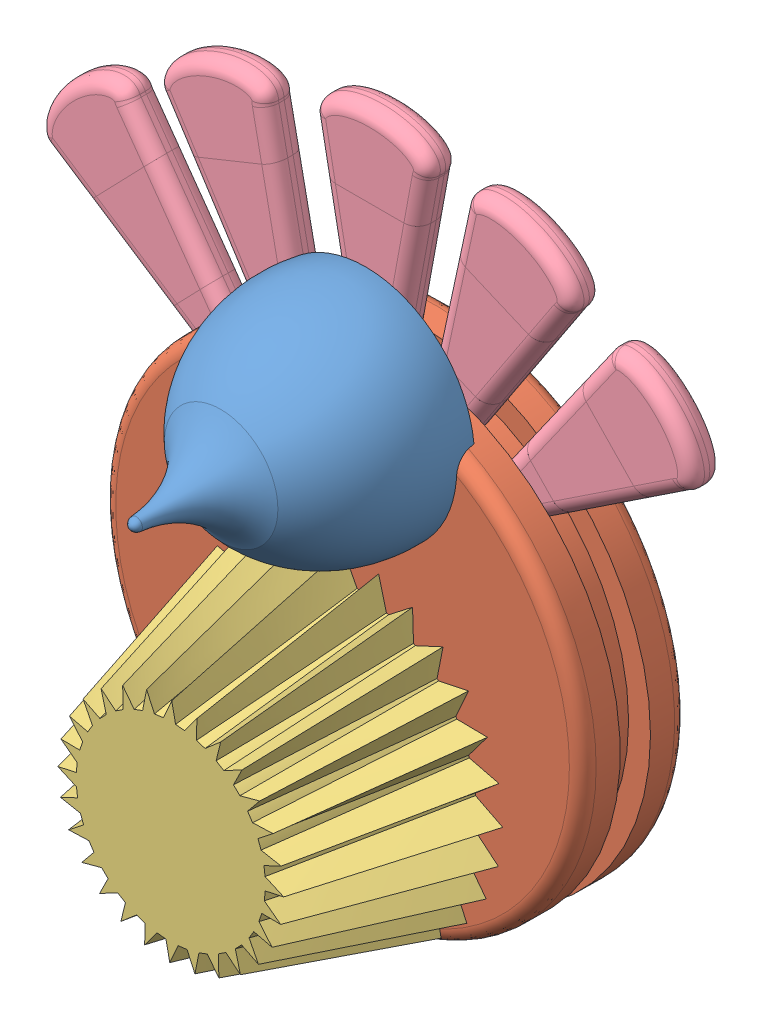
SolidWorks assembly Turkey, configuration Default. Lengths in mm.
Overall size (66.65 64.87 30.58).
8 component instances, 4 part files, 0 mates.
Components (placement in the parent):
- Hershey's Kiss-1: Hershey's Kiss [Default] at (-24.4933 25.1018 18.5343) x (0.008727 0 -0.999962) z (0.999962 0 0.008727) size (22.29 21.15 21.15)
- Oreo-1: Oreo [Default] at (-24.9548 11.0277 33.7479) size (45.89 45.77 10.16)
- Reese's Cup-1: Reese's Cup [Default] at (-24.9226 3.0054 37.3859) x (1 0 0) z (0 0.999962 -0.008727) size (30.52 16.4 30.52)
- candy corn-2: candy corn [Default] at (-20.6847 26.0601 30.748) x (0.920505 -0.390731 0) z (0 0 1) size (12.28 25.67 3.15)
- candy corn-3: candy corn [Default] at (-15.9954 23.4653 30.5632) x (0.694658 -0.71934 0) z (0 0 1) size (12.28 25.67 3.15)
- candy corn-4: candy corn [Default] at (-25.8598 26.6194 30.7152) size (12.28 25.67 3.15)
- candy corn-5: candy corn [Default] at (-32.4774 24.8038 30.7124) x (0.927184 0.374607 0) z (0 0 1) size (12.28 25.67 3.15)
- candy corn-6: candy corn [Default] at (-36.7105 22.1121 30.7977) x (0.694658 0.71934 0) z (0 0 1) size (12.28 25.67 3.15)
